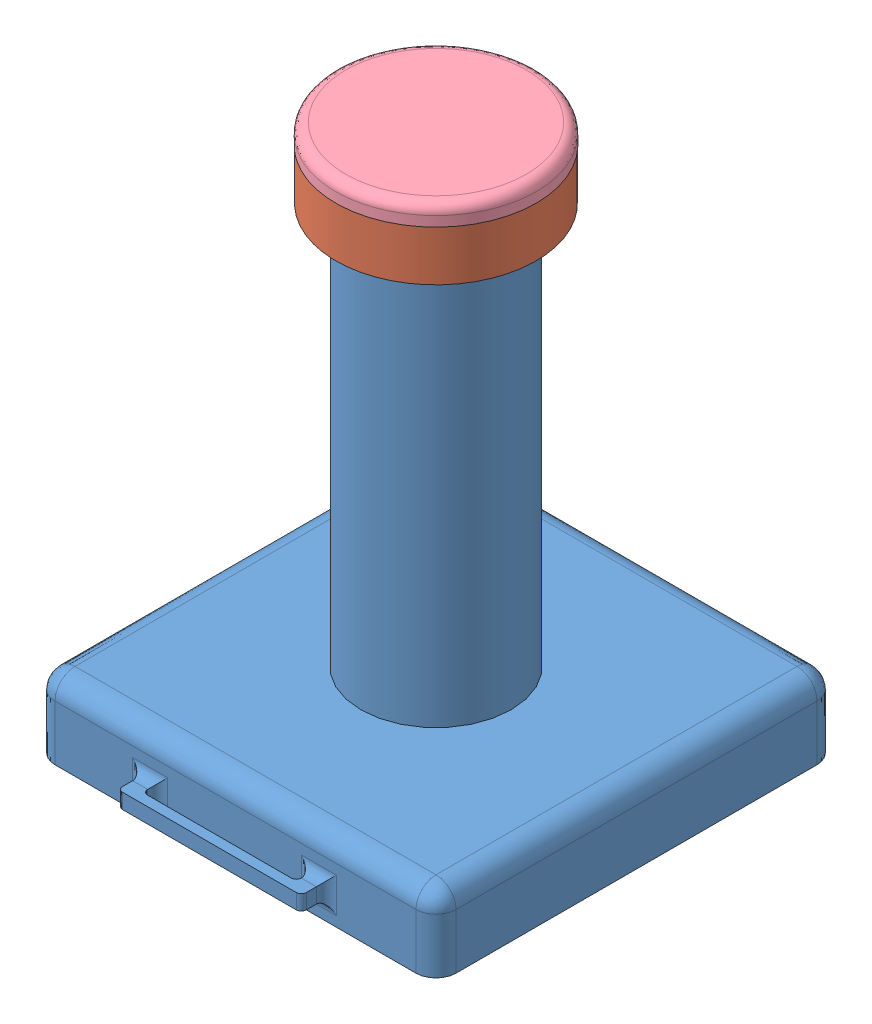
SolidWorks assembly Vaccine Assembly, configuration Default. Lengths in mm.
Overall size (101.6 138.43 114.3).
4 component instances, 4 part files, 6 mates.
Components (placement in the parent):
- Vaccine Main Body-1: Vaccine Main Body [Default] at origin size (101.6 120.65 114.3)
- Button attachment-1: Button attachment [Default] at (1.933 110.49 -9.8355) x (-0.975855 0 0.21842) z (-0.21842 0 -0.975855) size (50.68 23.41 50.68)
- Vaccine Plunger-2: Vaccine Plunger [Default] at (1.933 80.01 -9.8355) size (32.51 28.08 32.51)
- Buttone top part-1: Buttone top part [Default] at (1.933 91.44 -9.8355) x (0.783696 0 0.621145) z (-0.621145 0 0.783696) size (50.8 47.42 50.8)
Mates (geometry in assembly coordinates):
- Concentric3: concentric aligned: circle of Vaccine Main Body-1; circle of Button attachment-1
- Coincident3: coincident anti-aligned: plane of Vaccine Main Body-1 through (1.933 120.65 -9.8355) normal (0 1 0); plane of Button attachment-1 through (1.933 120.65 -9.8355) normal (0 -1 0)
- Concentric4: concentric aligned: circle of Vaccine Plunger-2; circle of Buttone top part-1
- Coincident6: coincident anti-aligned: plane of Vaccine Plunger-2 through (1.933 107.95 -9.8355) normal (0 1 0); plane of Buttone top part-1 through (1.933 107.95 -9.8355) normal (0 -1 0)
- Concentric6: concentric aligned: circle of Button attachment-1; circle of Buttone top part-1
- Coincident8: coincident anti-aligned: plane of Button attachment-1 through (1.933 133.35 -9.8355) normal (0 1 0); plane of Buttone top part-1 through (1.933 133.35 -9.8355) normal (0 -1 0)
